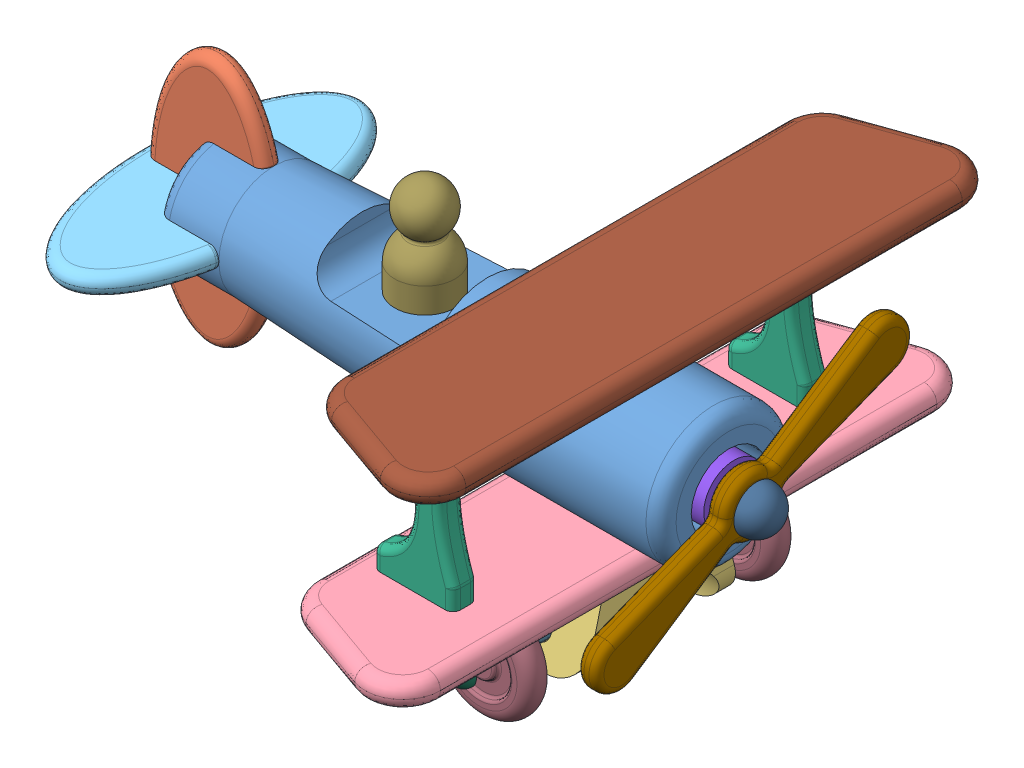
SolidWorks assembly wooden toy plane 組合件, configuration 預設. Lengths in mm.
Overall size (258.98 136.08 227.55).
27 component instances, 16 part files, 61 mates.
Components (placement in the parent):
- 110_2_SolidWorks_HW03-13-1: 110_2_SolidWorks_HW03-13 [預設] at (-59.864 -21.0649 206.3005) size (206.3 54 54)
- 110_2_SolidWorks_HW04-14-1: 110_2_SolidWorks_HW04-14 [預設] at (-95.3343 -21.0659 210.3005) x (0 1 0) z (0 0 -1) size (105.88 53.65 8.45)
- 110_2_SolidWorks_HW04-16-1: 110_2_SolidWorks_HW04-16 [預設] at (42.1657 -88.0649 206.3005) x (0 0 -1) z (1 0 0) size (64 39 40)
- 110_2_SolidWorks_HW02-10-1: 110_2_SolidWorks_HW02-10 [預設] at (88.6679 -53.0649 210.2466) x (0 0 1) z (0 1 0) size (227.55 60 10)
- 110_2_SolidWorks_HW04-15-1: 110_2_SolidWorks_HW04-15 [預設] at (-97.8343 -25.0649 206.3005) x (0 0 1) z (0 1 0) size (132.02 63.94 12.07)
- 110_2_SolidWorks_HW03-12-1: 110_2_SolidWorks_HW03-12 [預設] at (73.3381 -31.6432 131.3005) x (0 -1 0) z (0 0 1) size (65 48.6 12.4)
- 110_2_SolidWorks_HW01_02-1: 110_2_SolidWorks_HW01_02 [預設] at (59.3381 14.4351 136.3005) size (4 15 4)
- 110_2_SolidWorks_HW01_02-2: 110_2_SolidWorks_HW01_02 [預設] at (49.1657 -50.5649 136.3005) size (4 15 4)
- 110_2_SolidWorks_HW01_02-3: 110_2_SolidWorks_HW01_02 [預設] at (65.1657 -50.5649 136.3005) size (4 15 4)
- 110_2_SolidWorks_HW01_02-4: 110_2_SolidWorks_HW01_02 [預設] at (75.3381 14.4351 136.3005) size (4 15 4)
- 110_2_SolidWorks_HW01_02-9: 110_2_SolidWorks_HW01_02 [預設] at (75.3381 14.4351 276.3005) size (4 15 4)
- 110_2_SolidWorks_HW01_02-10: 110_2_SolidWorks_HW01_02 [預設] at (49.1657 -50.5649 276.3005) x (-0.971245 0 0.238083) z (-0.238083 0 -0.971245) size (4 15 4)
- 110_2_SolidWorks_HW01_02-11: 110_2_SolidWorks_HW01_02 [預設] at (65.1657 -50.5649 276.3005) size (4 15 4)
- 110_2_SolidWorks_HW01_02-12: 110_2_SolidWorks_HW01_02 [預設] at (59.3381 14.4351 276.3005) size (4 15 4)
- 110_2_SolidWorks_HW03-12-3: 110_2_SolidWorks_HW03-12 [預設] at (73.3381 -31.6432 271.3005) x (0 -1 0) z (0 0 1) size (65 48.6 12.4)
- 110_2_SolidWorks_HW01_01-1: 110_2_SolidWorks_HW01_01 [預設] at (110.1657 -21.0649 206.3005) x (0 -0.881929 0.471382) z (-1 0 0) size (24 24 40)
- 110_2_SolidWorks_HW03-11-1: 110_2_SolidWorks_HW03-11 [預設] at (118.6657 -21.0649 206.3005) x (0 0.462286 -0.886731) z (-1 0 0) size (140 24 8)
- 110_2_SolidWorks_HW01_03-1: 110_2_SolidWorks_HW01_03 [預設] at (119.1657 -21.0649 206.3005) x (-1 0 0) z (0 -0.209851 0.977733) size (30 18 18)
- 110_2_SolidWorks_HW02-09-1: 110_2_SolidWorks_HW02-09 [預設] at (98.8403 31.9351 202.3543) x (0 0 -1) z (0 -1 0) size (227.55 60 10)
- 110_2_SolidWorks_HW02-07-1: 110_2_SolidWorks_HW02-07 [預設] at (-12.8343 2.3654 206.3005) x (-0.785112 0 -0.619354) z (0.619354 0 -0.785112) size (24 55 24)
- 110_2_SolidWorks_HW02-08-1: 110_2_SolidWorks_HW02-08 [預設] at (62.1657 -76.0649 159.8667) x (0 0 -1) z (-0.885082 0.465434 0) size (10.13 40 40)
- 110_2_SolidWorks_HW02-08-2: 110_2_SolidWorks_HW02-08 [預設] at (62.1657 -76.0649 256.8667) x (0 0 -1) z (0.786499 0.617591 0) size (10.13 40 40)
- 110_2_SolidWorks_HW01_04-1: 110_2_SolidWorks_HW01_04 [預設] at (62.1657 -76.0649 243.8005) x (-0.794274 -0.60756 0) z (0.60756 -0.794274 0) size (8 75 8)
- 110_2_SolidWorks_HW01_06-1: 110_2_SolidWorks_HW01_06 [預設] at (62.1657 -76.0649 265.8005) x (0 0 1) z (0.555933 0.831227 0) size (31 10 10)
- 110_2_SolidWorks_HW01_06-2: 110_2_SolidWorks_HW01_06 [預設] at (62.1657 -76.0649 146.8005) x (0 0 -1) z (0.534832 -0.844958 0) size (31 10 10)
- 110_2_SolidWorks_HW01_05-1: 110_2_SolidWorks_HW01_05 [預設] at (62.1657 -31.0649 194.3005) x (0.790048 0 0.613045) z (0 -1 0) size (6 6 32)
- 110_2_SolidWorks_HW01_05-2: 110_2_SolidWorks_HW01_05 [預設] at (62.1657 -63.0649 218.3005) x (0.419619 0 -0.9077) z (0 1 0) size (6 6 32)
Mates (geometry in assembly coordinates):
- 重合/共線/共點4: coincident aligned: circle of 110_2_SolidWorks_HW03-13-1; circle of 110_2_SolidWorks_HW02-10-1
- 同軸心1: concentric aligned: cylinder of 110_2_SolidWorks_HW03-13-1 through (62.1657 -31.0649 218.3005) axis (0 -1 0) radius 3; cylinder of 110_2_SolidWorks_HW02-10-1 through (62.1657 -43.0649 218.3005) axis (0 -1 0) radius 3
- 重合/共線/共點11: coincident anti-aligned: plane of 110_2_SolidWorks_HW04-14-1 through (-97.8343 -25.0649 202.3005) normal (-1 0 0); plane of 110_2_SolidWorks_HW04-15-1 through (-97.8343 -17.0649 202.3005) normal (1 0 0)
- 重合/共線/共點12: coincident anti-aligned: plane of 110_2_SolidWorks_HW04-14-1 through (-97.8343 -17.0649 202.3005) normal (0 -1 0); plane of 110_2_SolidWorks_HW04-15-1 through (-97.8343 -17.0649 206.3005) normal (0 1 0)
- 重合/共線/共點13: coincident anti-aligned: plane of 110_2_SolidWorks_HW04-14-1 through (-95.3343 -21.0659 202.3005) normal (0 0 -1); plane of 110_2_SolidWorks_HW04-15-1 through (-72.8343 -17.0649 202.3005) normal (0 0 1)
- 同軸心2: concentric anti-aligned: cylinder of 110_2_SolidWorks_HW03-13-1 through (-76.8343 -48.0649 206.3005) axis (0 1 0) radius 4; cylinder of 110_2_SolidWorks_HW04-14-1 through (-76.8343 -42.8604 206.3005) axis (0 -1 0) radius 4
- 同軸心3: concentric aligned: cylinder of 110_2_SolidWorks_HW03-13-1 through (-76.8343 -21.0649 233.3005) axis (0 0 -1) radius 4; cylinder of 110_2_SolidWorks_HW04-15-1 through (-76.8343 -21.0649 183.6382) axis (0 0 -1) radius 4
- 重合/共線/共點14: coincident anti-aligned: plane of 110_2_SolidWorks_HW03-12-1 through (59.3381 14.4351 136.3005) normal (0 1 0); plane of 110_2_SolidWorks_HW01_02-1 through (59.3381 14.4351 136.3005) normal (0 -1 0)
- 同軸心4: concentric anti-aligned: cylinder of 110_2_SolidWorks_HW03-12-1 through (59.3381 14.4351 136.3005) axis (0 1 0) radius 2; cylinder of 110_2_SolidWorks_HW01_02-1 through (59.3381 29.4351 136.3005) axis (0 -1 0) radius 2
- 重合/共線/共點15: coincident anti-aligned: circle of 110_2_SolidWorks_HW03-12-1; plane of 110_2_SolidWorks_HW01_02-4 through (75.3381 14.4351 136.3005) normal (0 -1 0)
- 同軸心5: concentric anti-aligned: cylinder of 110_2_SolidWorks_HW03-12-1 through (75.3381 14.4351 136.3005) axis (0 1 0) radius 2; cylinder of 110_2_SolidWorks_HW01_02-4 through (75.3381 29.4351 136.3005) axis (0 -1 0) radius 2
- 重合/共線/共點16: coincident anti-aligned: plane of 110_2_SolidWorks_HW03-12-1 through (65.1657 -35.5649 136.3005) normal (0 -1 0); plane of 110_2_SolidWorks_HW01_02-3 through (65.1657 -35.5649 136.3005) normal (0 1 0)
- 同軸心6: concentric aligned: cylinder of 110_2_SolidWorks_HW03-12-1 through (65.1657 -35.5649 136.3005) axis (0 -1 0) radius 2; cylinder of 110_2_SolidWorks_HW01_02-3 through (65.1657 -35.5649 136.3005) axis (0 -1 0) radius 2
- 重合/共線/共點17: coincident anti-aligned: plane of 110_2_SolidWorks_HW03-12-1 through (49.1657 -35.5649 136.3005) normal (0 -1 0); plane of 110_2_SolidWorks_HW01_02-2 through (49.1657 -35.5649 136.3005) normal (0 1 0)
- 同軸心7: concentric aligned: cylinder of 110_2_SolidWorks_HW03-12-1 through (49.1657 -35.5649 136.3005) axis (0 -1 0) radius 2; cylinder of 110_2_SolidWorks_HW01_02-2 through (49.1657 -35.5649 136.3005) axis (0 -1 0) radius 2
- 同軸心12: concentric anti-aligned: cylinder of 110_2_SolidWorks_HW02-10-1 through (65.1657 -50.5649 136.3005) axis (0 1 0) radius 2; cylinder of 110_2_SolidWorks_HW01_02-3 through (65.1657 -35.5649 136.3005) axis (0 -1 0) radius 2
- 同軸心13: concentric anti-aligned: circle of 110_2_SolidWorks_HW02-10-1; circle of 110_2_SolidWorks_HW01_02-2
- 重合/共線/共點23: coincident anti-aligned: plane of 110_2_SolidWorks_HW01_02-11 through (65.1657 -35.5649 276.3005) normal (0 1 0); plane of 110_2_SolidWorks_HW03-12-3 through (65.1657 -35.5649 276.3005) normal (0 -1 0)
- 同軸心14: concentric aligned: cylinder of 110_2_SolidWorks_HW01_02-11 through (65.1657 -35.5649 276.3005) axis (0 -1 0) radius 2; cylinder of 110_2_SolidWorks_HW03-12-3 through (65.1657 -35.5649 276.3005) axis (0 -1 0) radius 2
- 同軸心15: concentric aligned: cylinder of 110_2_SolidWorks_HW01_02-10 through (49.1657 -35.5649 276.3005) axis (0 -1 0) radius 2; cylinder of 110_2_SolidWorks_HW03-12-3 through (49.1657 -35.5649 276.3005) axis (0 -1 0) radius 2
- 重合/共線/共點25: coincident anti-aligned: plane of 110_2_SolidWorks_HW01_02-9 through (75.3381 14.4351 276.3005) normal (0 -1 0); plane of 110_2_SolidWorks_HW03-12-3 through (75.3381 14.4351 276.3005) normal (0 1 0)
- 同軸心17: concentric anti-aligned: cylinder of 110_2_SolidWorks_HW01_02-9 through (75.3381 29.4351 276.3005) axis (0 -1 0) radius 2; cylinder of 110_2_SolidWorks_HW03-12-3 through (75.3381 14.4351 276.3005) axis (0 1 0) radius 2
- 重合/共線/共點26: coincident anti-aligned: plane of 110_2_SolidWorks_HW01_02-12 through (59.3381 14.4351 276.3005) normal (0 -1 0); circle of 110_2_SolidWorks_HW03-12-3
- 同軸心18: concentric anti-aligned: cylinder of 110_2_SolidWorks_HW01_02-12 through (59.3381 29.4351 276.3005) axis (0 -1 0) radius 2; cylinder of 110_2_SolidWorks_HW03-12-3 through (59.3381 14.4351 276.3005) axis (0 1 0) radius 2
- 同軸心20: concentric anti-aligned: cylinder of 110_2_SolidWorks_HW02-10-1 through (65.1657 -50.5649 276.3005) axis (0 1 0) radius 2; cylinder of 110_2_SolidWorks_HW01_02-11 through (65.1657 -35.5649 276.3005) axis (0 -1 0) radius 2
- 同軸心21: concentric anti-aligned: cylinder of 110_2_SolidWorks_HW02-10-1 through (49.1657 -50.5649 276.3005) axis (0 1 0) radius 2; cylinder of 110_2_SolidWorks_HW01_02-10 through (49.1657 -35.5649 276.3005) axis (0 -1 0) radius 2
- 同軸心22: concentric anti-aligned: cylinder of 110_2_SolidWorks_HW03-13-1 through (-114.4247 -21.0649 206.3005) axis (-1 0 0) radius 6; cylinder of 110_2_SolidWorks_HW01_01-1 through (70.1657 -21.0649 206.3005) axis (1 0 0) radius 6
- 重合/共線/共點31: coincident anti-aligned: plane of 110_2_SolidWorks_HW03-13-1 through (90.1657 -15.0649 206.3005) normal (1 0 0); plane of 110_2_SolidWorks_HW01_01-1 through (90.1657 -21.0649 206.3005) normal (-1 0 0)
- 同軸心23: concentric aligned: cylinder of 110_2_SolidWorks_HW03-11-1 through (110.6657 -21.0649 206.3005) axis (1 0 0) radius 5; cylinder of 110_2_SolidWorks_HW01_03-1 through (119.1657 -21.0649 206.3005) axis (1 0 0) radius 5
- 同軸心25: concentric aligned: cylinder of 110_2_SolidWorks_HW01_01-1 through (98.1657 -21.0649 206.3005) axis (1 0 0) radius 5; cylinder of 110_2_SolidWorks_HW01_03-1 through (119.1657 -21.0649 206.3005) axis (1 0 0) radius 5
- 重合/共線/共點34: coincident anti-aligned: plane of 110_2_SolidWorks_HW01_01-1 through (98.1657 -21.0649 206.3005) normal (1 0 0); plane of 110_2_SolidWorks_HW01_03-1 through (98.1657 -21.0649 206.3005) normal (-1 0 0)
- 寬度2: width aligned: plane of 110_2_SolidWorks_HW01_01-1 through (110.1657 -21.0649 206.3005) normal (1 0 0); plane of 110_2_SolidWorks_HW01_03-1 through (119.1657 -20.0156 201.4118) normal (-1 0 0); plane of 110_2_SolidWorks_HW03-11-1 through (118.6657 6.6723 153.0966) normal (1 0 0); plane of 110_2_SolidWorks_HW03-11-1 through (110.6657 6.6723 153.0966) normal (-1 0 0)
- 同軸心26: concentric aligned: cylinder of 110_2_SolidWorks_HW01_02-1 through (59.3381 29.4351 136.3005) axis (0 -1 0) radius 2; cylinder of 110_2_SolidWorks_HW02-09-1 through (59.3381 29.4351 136.3005) axis (0 -1 0) radius 2
- 同軸心27: concentric aligned: cylinder of 110_2_SolidWorks_HW01_02-9 through (75.3381 29.4351 276.3005) axis (0 -1 0) radius 2; cylinder of 110_2_SolidWorks_HW02-09-1 through (75.3381 29.4351 276.3005) axis (0 -1 0) radius 2
- 同軸心28: concentric aligned: cylinder of 110_2_SolidWorks_HW01_02-12 through (59.3381 29.4351 276.3005) axis (0 -1 0) radius 2; cylinder of 110_2_SolidWorks_HW02-09-1 through (59.3381 29.4351 276.3005) axis (0 -1 0) radius 2
- 同軸心29: concentric aligned: cylinder of 110_2_SolidWorks_HW01_02-4 through (75.3381 29.4351 136.3005) axis (0 -1 0) radius 2; cylinder of 110_2_SolidWorks_HW02-09-1 through (75.3381 29.4351 136.3005) axis (0 -1 0) radius 2
- 同軸心30: concentric anti-aligned: circle of 110_2_SolidWorks_HW01_02-1; circle of 110_2_SolidWorks_HW02-09-1
- 同軸心31: concentric anti-aligned: cylinder of 110_2_SolidWorks_HW03-13-1 through (-12.8343 -28.0649 206.3005) axis (0 1 0) radius 12; cylinder of 110_2_SolidWorks_HW02-07-1 through (-12.8343 -18.3245 206.3005) axis (0 -1 0) radius 12
- 重合/共線/共點37: coincident anti-aligned: plane of 110_2_SolidWorks_HW03-13-1 through (-12.8343 -28.0649 206.3005) normal (0 1 0); plane of 110_2_SolidWorks_HW02-07-1 through (-3.413 -28.0649 213.7327) normal (0 -1 0)
- 同軸心32: concentric anti-aligned: cylinder of 110_2_SolidWorks_HW02-08-1 through (62.1657 -76.0649 152.6693) axis (0 0 1) radius 2.25; cylinder of 110_2_SolidWorks_HW01_06-2 through (62.1657 -76.0649 146.8005) axis (0 0 -1) radius 2
- 同軸心33: concentric aligned: cylinder of 110_2_SolidWorks_HW02-08-2 through (62.1657 -76.0649 249.6693) axis (0 0 1) radius 2.25; cylinder of 110_2_SolidWorks_HW01_06-1 through (62.1657 -76.0649 265.8005) axis (0 0 1) radius 2
- 同軸心34: concentric aligned: cylinder of 110_2_SolidWorks_HW01_04-1 through (62.1657 -76.0649 239.8005) axis (0 0 1) radius 2; cylinder of 110_2_SolidWorks_HW01_06-1 through (62.1657 -76.0649 265.8005) axis (0 0 1) radius 2
- 同軸心35: concentric aligned: cylinder of 110_2_SolidWorks_HW01_04-1 through (62.1657 -76.0649 172.8005) axis (0 0 -1) radius 2; cylinder of 110_2_SolidWorks_HW01_06-2 through (62.1657 -76.0649 146.8005) axis (0 0 -1) radius 2
- 寬度3: width aligned: plane of 110_2_SolidWorks_HW01_06-2 through (63.8556 -74.9952 146.8005) normal (0 0 1); plane of 110_2_SolidWorks_HW01_04-1 through (62.1657 -76.0649 168.8005) normal (0 0 -1); plane of 110_2_SolidWorks_HW02-08-1 through (62.1657 -76.0649 162.8005) normal (0 0 1); plane of 110_2_SolidWorks_HW02-08-1 through (59.3731 -81.3753 152.8005) normal (0 0 -1)
- 同軸心36: concentric anti-aligned: cylinder of 110_2_SolidWorks_HW04-16-1 through (62.1657 -76.0649 238.3005) axis (0 0 -1) radius 4.25; cylinder of 110_2_SolidWorks_HW01_04-1 through (62.1657 -76.0649 168.8005) axis (0 0 1) radius 4
- 寬度5: width anti-aligned: plane of 110_2_SolidWorks_HW04-16-1 through (82.1657 -88.0649 174.3005) normal (0 0.249041 -0.968493); plane of 110_2_SolidWorks_HW04-16-1 through (82.1657 -53.0649 229.3005) normal (0 0.249041 0.968493); plane of 110_2_SolidWorks_HW01_04-1 through (62.1657 -76.0649 168.8005) normal (0 0 -1); plane of 110_2_SolidWorks_HW01_04-1 through (62.1657 -76.0649 243.8005) normal (0 0 1)
- 重合/共線/共點39: coincident anti-aligned: plane of 110_2_SolidWorks_HW01_04-1 through (62.1657 -76.0649 172.8005) normal (0 0 -1); plane of 110_2_SolidWorks_HW01_06-2 through (62.1657 -76.0649 172.8005) normal (0 0 1)
- 重合/共線/共點40: coincident anti-aligned: plane of 110_2_SolidWorks_HW01_04-1 through (62.1657 -76.0649 239.8005) normal (0 0 1); plane of 110_2_SolidWorks_HW01_06-1 through (62.1657 -76.0649 239.8005) normal (0 0 -1)
- 寬度6: width aligned: plane of 110_2_SolidWorks_HW01_06-1 through (63.8281 -77.1767 265.8005) normal (0 0 -1); plane of 110_2_SolidWorks_HW01_04-1 through (62.1657 -76.0649 243.8005) normal (0 0 1); plane of 110_2_SolidWorks_HW02-08-2 through (58.4601 -71.3459 249.8005) normal (0 0 -1); plane of 110_2_SolidWorks_HW02-08-2 through (62.1657 -76.0649 259.8005) normal (0 0 1)
- 重合/共線/共點41: coincident anti-aligned: plane of 110_2_SolidWorks_HW01_02-10 through (49.1657 -35.5649 276.3005) normal (0 1 0); plane of 110_2_SolidWorks_HW03-12-3 through (49.1657 -35.5649 276.3005) normal (0 -1 0)
- 重合/共線/共點43: coincident anti-aligned: circle of 110_2_SolidWorks_HW01_02-9; plane of 110_2_SolidWorks_HW02-09-1 through (75.3381 29.4351 276.3005) normal (0 -1 0)
- 重合/共線/共點44: coincident anti-aligned: plane of 110_2_SolidWorks_HW01_02-4 through (75.3381 29.4351 136.3005) normal (0 1 0); plane of 110_2_SolidWorks_HW02-09-1 through (75.3381 29.4351 136.3005) normal (0 -1 0)
- 重合/共線/共點45: coincident anti-aligned: plane of 110_2_SolidWorks_HW02-10-1 through (65.1657 -50.5649 276.3005) normal (0 1 0); plane of 110_2_SolidWorks_HW01_02-11 through (65.1657 -50.5649 276.3005) normal (0 -1 0)
- 同軸心37: concentric aligned: cylinder of 110_2_SolidWorks_HW04-16-1 through (62.1657 -63.0649 194.3005) axis (0 1 0) radius 3; cylinder of 110_2_SolidWorks_HW01_05-1 through (62.1657 -63.0649 194.3005) axis (0 1 0) radius 3
- 同軸心39: concentric anti-aligned: cylinder of 110_2_SolidWorks_HW02-10-1 through (62.1657 -43.0649 194.3005) axis (0 -1 0) radius 3; cylinder of 110_2_SolidWorks_HW01_05-1 through (62.1657 -63.0649 194.3005) axis (0 1 0) radius 3
- 同軸心40: concentric aligned: cylinder of 110_2_SolidWorks_HW02-10-1 through (62.1657 -43.0649 218.3005) axis (0 -1 0) radius 3; cylinder of 110_2_SolidWorks_HW01_05-2 through (62.1657 -31.0649 218.3005) axis (0 -1 0) radius 3
- 相切1: tangent aligned: plane of 110_2_SolidWorks_HW01_05-1 through (62.1657 -31.0649 194.3005) normal (0 1 0); circle of 110_2_SolidWorks_HW03-13-1
- 同軸心41: concentric anti-aligned: circle of 110_2_SolidWorks_HW03-13-1; circle of 110_2_SolidWorks_HW01_05-2
- 重合/共線/共點46: coincident anti-aligned: circle of 110_2_SolidWorks_HW03-13-1; plane of 110_2_SolidWorks_HW01_05-2 through (62.1657 -31.0649 218.3005) normal (0 1 0)
- 重合/共線/共點47: coincident anti-aligned: circle of 110_2_SolidWorks_HW04-16-1; plane of 110_2_SolidWorks_HW01_05-1 through (62.1657 -63.0649 194.3005) normal (0 -1 0)
- 同軸心42: concentric anti-aligned: circle of 110_2_SolidWorks_HW04-16-1; circle of 110_2_SolidWorks_HW01_05-2
